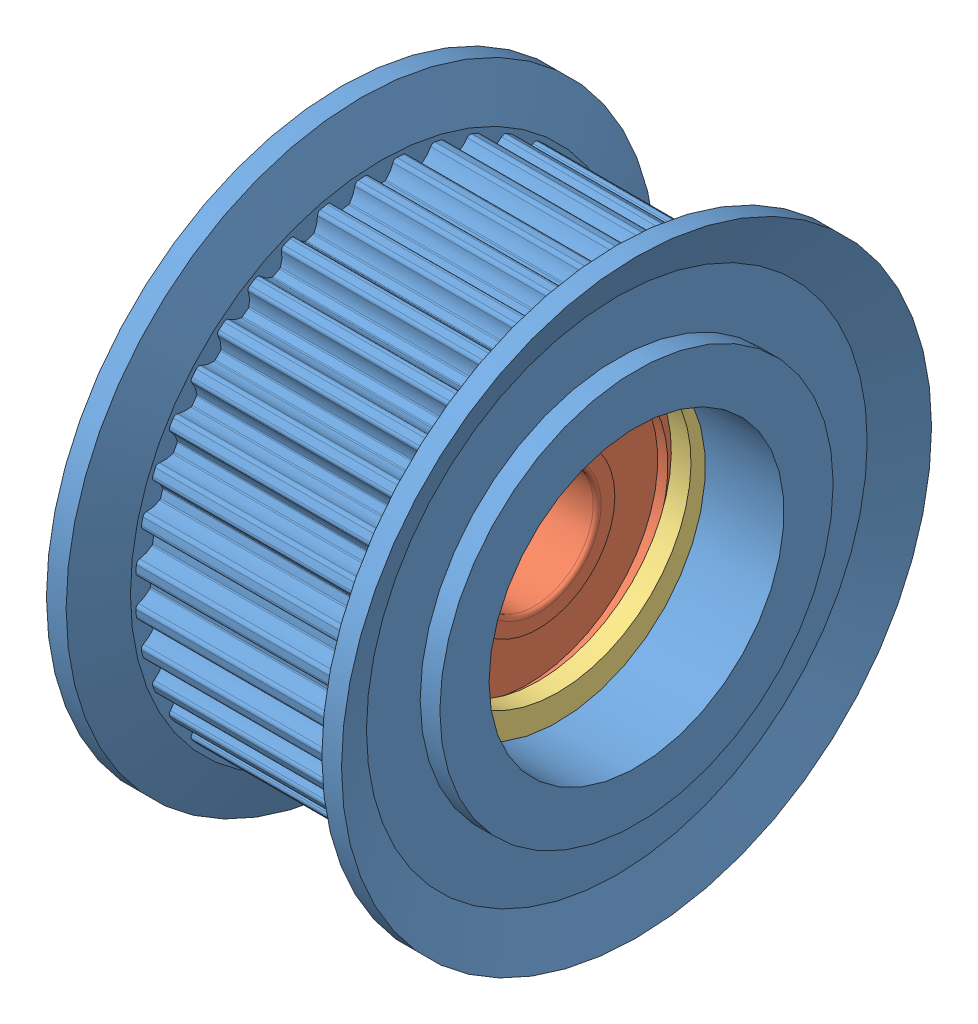
SolidWorks assembly Assem1, configuration Default. Lengths in mm.
Overall size (15 30 30).
3 component instances, 3 part files, 0 mates.
Components (placement in the parent):
- AHTF40S2M100flanged_idlers-1: AHTF40S2M100flanged_idlers [Default] at origin size (15 30 30)
- B696ZZ-1: B696ZZ [Default] at (2.5 0 0) x (-1 0 0) z (0 0 1) size (5 15 15)
- RTWS15-1: RTWS15 [Default] at (3 0 0) x (-1 0 0) z (0 0 1) size (1 15.83 16.2)
